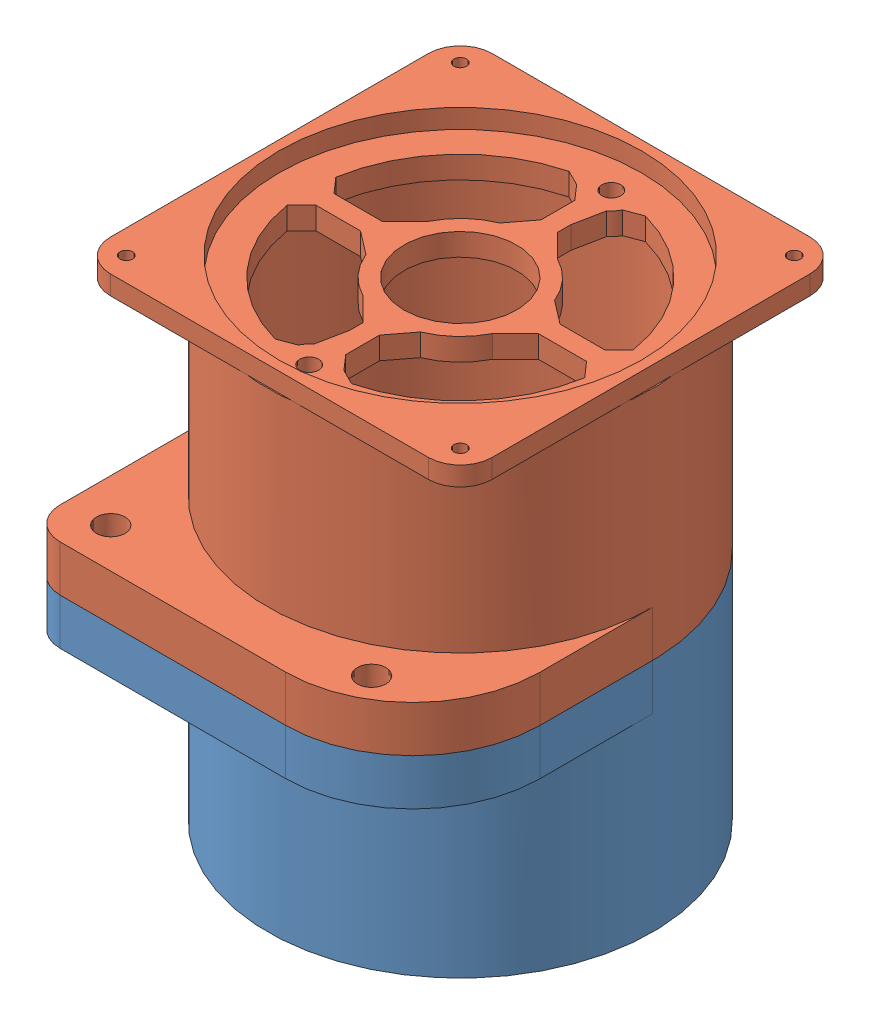
SolidWorks assembly Сборка картера электромотора, configuration По умолчанию. Lengths in mm.
Overall size (121 154 147.89).
2 component instances, 2 part files, 4 mates.
Components (placement in the parent):
- Левый Картер 1-1: Левый Картер 1 [По умолчанию] at (107.0507 43.1594 105.9325) size (121 77 147.89)
- Правый Картер 1-1: Правый Картер 1 [По умолчанию] at (107.0507 43.1594 105.9325) size (121 83 147.89)
Mates (geometry in assembly coordinates):
- Параллельность3: parallel aligned: plane of Левый Картер 1-1 through (107.0507 102.6594 181.3205) normal (0 0 1); plane of Правый Картер 1-1 through (107.0507 131.6594 181.3205) normal (0 0 1)
- Расстояние3: distance = 0 mm anti-aligned: plane of Левый Картер 1-1 through (107.0507 120.1594 105.9325) normal (0 1 0); plane of Правый Картер 1-1 through (107.0507 120.1594 105.9325) normal (0 -1 0)
- Расстояние4: distance = 0 mm aligned: plane of Правый Картер 1-1 through (46.5507 131.6594 105.9325) normal (-1 0 0); plane of Левый Картер 1-1 through (46.5507 102.6594 105.9325) normal (-1 0 0)
- Расстояние5: distance = 0 mm aligned: plane of Правый Картер 1-1 through (107.0507 131.6594 181.3205) normal (0 0 1); plane of Левый Картер 1-1 through (107.0507 102.6594 181.3205) normal (0 0 1)
